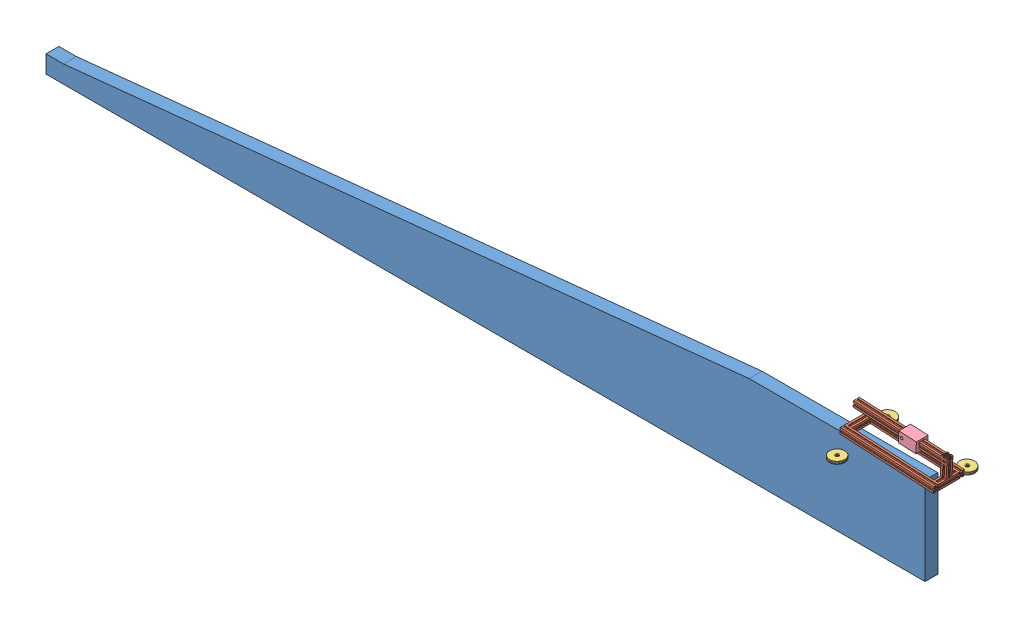
SolidWorks assembly BeeAssembly, configuration Default. Lengths in mm.
Overall size (1546.25 211.98 118.36).
11 component instances, 4 part files, 22 mates.
Components (placement in the parent):
- BeeFloor-1: BeeFloor [Default] at (-554.5897 664.2761 1362.2771) size (1500 150 22)
- Makerbeam50-1000mm-2: Makerbeam50-1000mm [160mm] at (826.9171 841.3023 1363.7971) x (0 0 1) z (0.998714 -0.050704 0) size (10 10 160)
- Makerbeam50-1000mm-3: Makerbeam50-1000mm [160mm] at (826.9171 841.3023 1405.7971) x (0 0 1) z (0.998714 -0.050704 0) size (10 10 160)
- BeeWheel-1: BeeWheel [Défaut] at (973.3622 825.6569 1340.2643) x (-0.608744 0.030905 -0.792765) z (0.791745 -0.040196 -0.609528) size (25.9 5.4 25.9)
- BeeWheel-2: BeeWheel [Défaut] at (839.4347 832.4563 1341.8945) x (0.836092 -0.042448 -0.546944) z (0.546241 -0.027732 0.837169) size (25.9 5.4 25.9)
- Makerbeam50-1000mm-4: Makerbeam50-1000mm [32mm] at (831.9107 841.0488 1368.7971) x (0.998714 -0.050704 0) z (0 0 1) size (10 10 32)
- BeeWheel-3: BeeWheel [Défaut] at (838.7137 817.2641 1427.5196) size (25.9 5.4 25.9)
- Makerbeam50-1000mm-5: Makerbeam50-1000mm [32mm] at (981.7178 833.4432 1368.7971) x (0.998714 -0.050704 0) z (0 0 1) size (10 10 32)
- Makerbeam50-1000mm-6: Makerbeam50-1000mm [160mm] at (988.2325 863.1511 1384.7971) x (0 0 -1) z (-0.998714 0.050704 0) size (10 10 160)
- BeeTractorSupport-1: BeeTractorSupport [Default] at (910.5724 866.0926 1384.5971) x (0 0 1) z (0.998714 -0.050704 0) size (20 21.37 30)
- Makerbeam50-1000mm-7: Makerbeam50-1000mm [32mm] at (981.9713 838.4368 1384.7971) x (0 0 1) z (0.050704 0.998714 0) size (10 10 32)
Mates (geometry in assembly coordinates):
- Coïncidente1: coincident anti-aligned: plane of Makerbeam50-1000mm-2 through (986.4578 828.1961 1358.7971) normal (-0.050704 -0.998714 0); plane of BeeWheel-1 through (972.6114 828.8991 1339.0752) normal (0.050704 0.998714 0)
- Coïncidente2: coincident anti-aligned: plane of Makerbeam50-1000mm-2 through (986.4578 828.1961 1358.7971) normal (-0.050704 -0.998714 0); plane of BeeWheel-2 through (840.8511 835.5885 1341.0741) normal (0.050704 0.998714 0)
- Coïncidente3: coincident aligned: plane of Makerbeam50-1000mm-2 through (986.4578 828.1961 1365.2971) normal (-0.050704 -0.998714 0); plane of Makerbeam50-1000mm-3 through (986.4578 828.1961 1400.7971) normal (-0.050704 -0.998714 0)
- Coïncidente4: coincident aligned: plane of Makerbeam50-1000mm-2 through (986.7113 833.1897 1363.7971) normal (0.998714 -0.050704 0); plane of Makerbeam50-1000mm-3 through (986.7113 833.1897 1405.7971) normal (0.998714 -0.050704 0)
- Distance1: distance = 32 mm anti-aligned: plane of Makerbeam50-1000mm-2 through (986.4578 828.1961 1368.7971) normal (0 0 1); plane of Makerbeam50-1000mm-3 through (986.6353 831.6916 1400.7971) normal (0 0 -1)
- Parallèle1: parallel anti-aligned: plane of BeeFloor-1 through (-554.5897 664.2761 1384.2771) normal (0 0 1); plane of Makerbeam50-1000mm-3 through (986.9649 838.1833 1400.7971) normal (0 0 -1)
- Tangent3: tangent aligned: plane of Makerbeam50-1000mm-2 through (826.9171 841.3023 1363.7971) normal (-0.998714 0.050704 0); cylinder of BeeWheel-2 through (840.3398 850.2833 1341.8945) axis (0.050704 0.998714 0) radius 12.95
- Tangent4: tangent aligned: plane of Makerbeam50-1000mm-2 through (986.7113 833.1897 1363.7971) normal (0.998714 -0.050704 0); cylinder of BeeWheel-1 through (974.2673 843.4839 1340.2643) axis (0.050704 0.998714 0) radius 12.95
- Coïncidente7: coincident aligned: plane of Makerbeam50-1000mm-2 through (826.9171 841.3023 1363.7971) normal (-0.998714 0.050704 0); plane of Makerbeam50-1000mm-4 through (826.9932 842.8004 1400.7971) normal (-0.998714 0.050704 0)
- Coïncidente8: coincident aligned: plane of Makerbeam50-1000mm-2 through (986.9649 838.1833 1365.2971) normal (0.050704 0.998714 0); plane of Makerbeam50-1000mm-4 through (833.6623 845.9663 1400.7971) normal (0.050704 0.998714 0)
- Coïncidente9: coincident anti-aligned: plane of Makerbeam50-1000mm-2 through (986.7874 834.6878 1368.7971) normal (0 0 1); plane of Makerbeam50-1000mm-4 through (831.9107 841.0488 1368.7971) normal (0 0 -1)
- Coïncidente10: coincident aligned: plane of Makerbeam50-1000mm-2 through (986.9649 838.1833 1365.2971) normal (0.050704 0.998714 0); plane of Makerbeam50-1000mm-5 through (983.4694 838.3607 1400.7971) normal (0.050704 0.998714 0)
- Coïncidente11: coincident aligned: plane of Makerbeam50-1000mm-2 through (986.7113 833.1897 1363.7971) normal (0.998714 -0.050704 0); plane of Makerbeam50-1000mm-5 through (986.9649 838.1833 1400.7971) normal (0.998714 -0.050704 0)
- Coïncidente12: coincident anti-aligned: plane of Makerbeam50-1000mm-2 through (986.7874 834.6878 1368.7971) normal (0 0 1); plane of Makerbeam50-1000mm-5 through (981.7178 833.4432 1368.7971) normal (0 0 -1)
- Coïncidente15: coincident aligned: plane of Makerbeam50-1000mm-4 through (826.9932 842.8004 1400.7971) normal (-0.998714 0.050704 0); plane of Makerbeam50-1000mm-6 through (828.4383 871.2638 1384.7971) normal (-0.998714 0.050704 0)
- Coïncidente17: coincident anti-aligned: plane of Makerbeam50-1000mm-6 through (828.6918 876.2573 1383.2971) normal (0.050704 0.998714 0); plane of BeeTractorSupport-1 through (940.838 870.5637 1383.1971) normal (-0.050704 -0.998714 0)
- Coïncidente18: coincident anti-aligned: plane of Makerbeam50-1000mm-6 through (828.6918 876.2573 1389.7971) normal (0 0 1); plane of BeeTractorSupport-1 through (940.6454 866.7686 1389.7971) normal (0 0 -1)
- Distance2: distance = 21 mm aligned: plane of Makerbeam50-1000mm-6 through (828.6918 876.2573 1389.7971) normal (0 0 1); plane of Makerbeam50-1000mm-3 through (986.7874 834.6878 1410.7971) normal (0 0 1)
- Distance3: distance = 20 mm anti-aligned: plane of Makerbeam50-1000mm-5 through (983.4694 838.3607 1400.7971) normal (0.050704 0.998714 0); plane of Makerbeam50-1000mm-6 through (828.1847 866.2702 1383.2971) normal (-0.050704 -0.998714 0)
- Coïncidente21: coincident anti-aligned: plane of Makerbeam50-1000mm-5 through (976.9777 838.6903 1400.7971) normal (0.050704 0.998714 0); plane of Makerbeam50-1000mm-7 through (981.9713 838.4368 1384.7971) normal (-0.050704 -0.998714 0)
- Coïncidente22: coincident aligned: plane of Makerbeam50-1000mm-5 through (986.9649 838.1833 1400.7971) normal (0.998714 -0.050704 0); plane of Makerbeam50-1000mm-7 through (988.5874 870.1421 1386.2971) normal (0.998714 -0.050704 0)
- Coïncidente23: coincident aligned: plane of Makerbeam50-1000mm-6 through (828.6918 876.2573 1389.7971) normal (0 0 1); plane of Makerbeam50-1000mm-7 through (982.0957 870.4717 1389.7971) normal (0 0 1)
